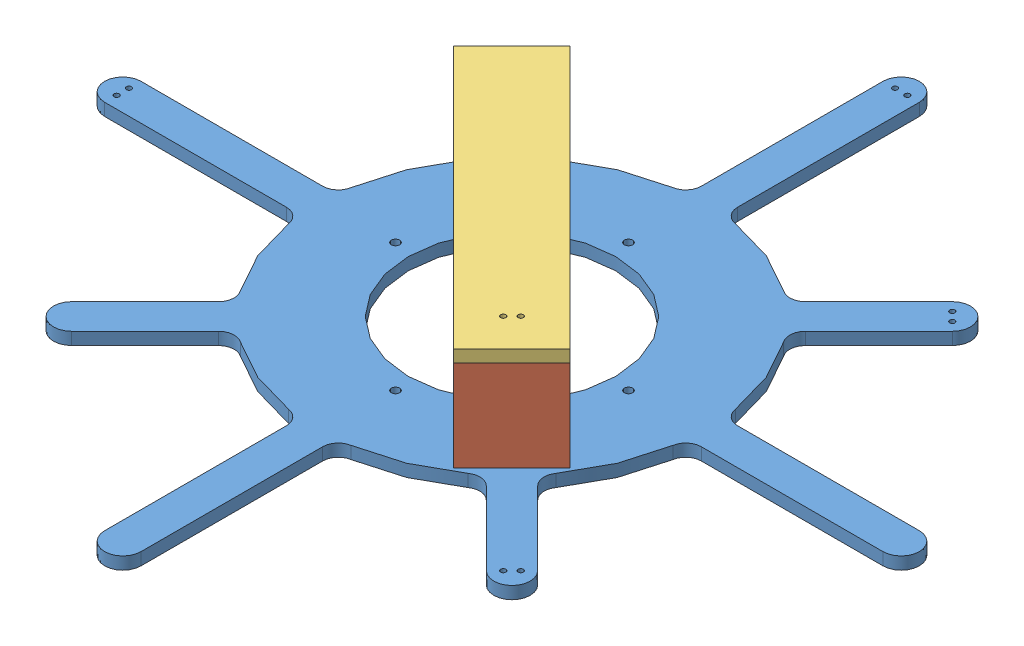
SolidWorks assembly Assem1, configuration Default. Lengths in mm.
Overall size (157 22.23 157).
4 component instances, 3 part files, 11 mates.
Components (placement in the parent):
- Acrylic_mount-1: Acrylic_mount [Default] at origin size (157 2.38 157)
- Acrylic_riser-1: Acrylic_riser [Default] at (-25.257 8.7312 -25.257) x (0.707107 0 -0.707107) z (0 1 0) size (15.88 2.38 17.46)
- Acrylic_riser-2: Acrylic_riser [Default] at (23.5723 8.7312 23.5723) x (0.707107 0 -0.707107) z (0 1 0) size (15.88 2.38 17.46)
- Acrylic_runner-1: Acrylic_runner [Default] at (0 19.8438 0) x (0.707107 0 -0.707107) z (0.707107 0 0.707107) size (15.88 2.38 71.44)
Mates (geometry in assembly coordinates):
- Coincident1: coordinate: point of Acrylic_mount-1; point of assembly
- Coincident2: coincident anti-aligned: plane of Acrylic_riser-1 through (-29.1849 17.4625 -17.9596) normal (0 1 0); plane of Acrylic_runner-1 through (0 17.4625 0) normal (0 -1 0)
- Coincident3: coincident aligned: plane of Acrylic_riser-1 through (-17.9596 0 -29.1849) normal (0.707107 0 -0.707107); plane of Acrylic_runner-1 through (-19.6443 17.4625 -30.8696) normal (0.707107 0 -0.707107)
- Coincident4: coincident anti-aligned: plane of Acrylic_riser-2 through (19.6443 17.4625 30.8696) normal (0 1 0); plane of Acrylic_runner-1 through (0 17.4625 0) normal (0 -1 0)
- Coincident5: coincident aligned: plane of Acrylic_riser-2 through (30.8696 0 19.6443) normal (0.707107 0 -0.707107); plane of Acrylic_runner-1 through (-19.6443 17.4625 -30.8696) normal (0.707107 0 -0.707107)
- Coincident6: coincident aligned: plane of Acrylic_riser-1 through (-25.257 8.7312 -25.257) normal (-0.707107 0 -0.707107); plane of Acrylic_runner-1 through (-30.8696 17.4625 -19.6443) normal (-0.707107 0 -0.707107)
- Coincident7: coincident aligned: plane of Acrylic_riser-2 through (25.257 8.7312 25.257) normal (0.707107 0 0.707107); plane of Acrylic_runner-1 through (19.6443 17.4625 30.8696) normal (0.707107 0 0.707107)
- Coincident8: coincident anti-aligned: plane of Acrylic_mount-1 through (0 0 0) normal (0 1 0); plane of Acrylic_riser-2 through (19.6443 0 30.8696) normal (0 -1 0)
- Parallel1: parallel aligned: plane of Acrylic_mount-1 through (-23.9259 -2.3813 -28.8756) normal (0.707107 0 -0.707107); plane of Acrylic_runner-1 through (-19.6443 17.4625 -30.8696) normal (0.707107 0 -0.707107)
- Width1: width anti-aligned: plane of Acrylic_runner-1 through (-19.6443 17.4625 -30.8696) normal (0.707107 0 -0.707107); plane of Acrylic_runner-1 through (-30.8696 17.4625 -19.6443) normal (-0.707107 0 0.707107); plane of Acrylic_mount-1 through (-44.9013 -2.3813 -39.9515) normal (-0.707107 0 0.707107); plane of Acrylic_mount-1 through (-23.9259 -2.3813 -28.8756) normal (0.707107 0 -0.707107)
- Coincident10: coincident: axis of Acrylic_mount-1 through (0 -2.3813 0) axis (0 1 0); point of Acrylic_runner-1
